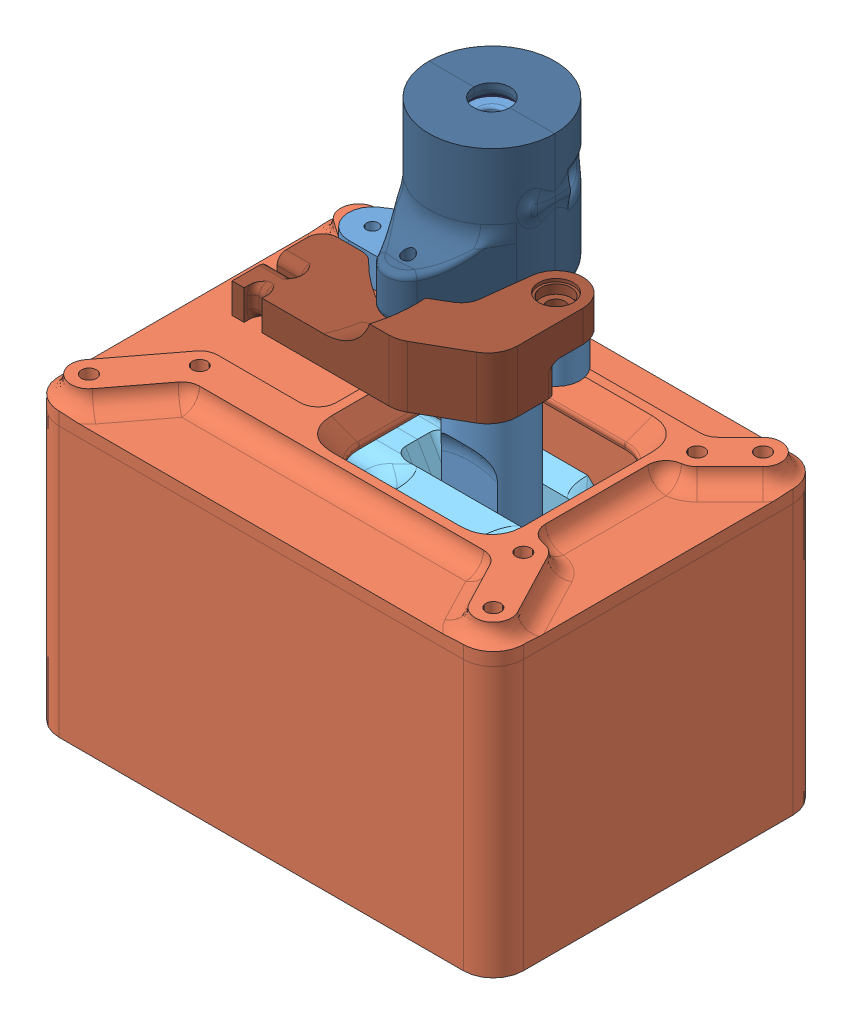
SolidWorks assembly Gimbal, configuration Default. Lengths in mm.
Overall size (155 197.27 110).
24 component instances, 11 part files, 54 mates.
Components (placement in the parent):
- Center Core-1: Center Core [Default] at (14.5 -56 0) size (77.28 158.27 34.47)
- Top Plate-1: Top Plate [Default] at origin size (155 100 110)
- Bearing Block A-1: Bearing Block A [Default] at (54 -21 0) x (0 0 -1) z (1 0 0) size (70 41 12)
- Bearing Block B-1: Bearing Block B [Default] at (-47 -18 0) x (0 0 -1) z (1 0 0) size (81.49 59 37.49)
- Axis B Block-1: Axis B Block [Default] at (14.5 -21 0) x (-1 0 0) z (0 0 -1) size (108 64.09 38.74)
- CAM Roll-1: CAM Roll [Default] at (47.5 -55.5 0) x (0.999997 0.002421 0) z (0 0 1) size (85.5 30 15.96)
- CAM Yaw-1: CAM Yaw [Default] at (-49.75 -49 35) x (0 0 1) z (-1 0 0) size (80 28 17.41)
- Bearing-1: Bearing [685] at (-45.5 -46 0) x (1 0 0) z (0 0.029576 0.999563) size (5 11 11)
- Bearing-2: Bearing [685] at (14.5 -51 4.5) x (0 0 1) z (-0.999911 0.013316 0) size (5 11 11)
- Bearing-3: Bearing [6802] at (14.5 -21 -10.5) x (0 0 1) z (-0.938422 -0.345492 0) size (5 24 24)
- Bearing-4: Bearing [6802] at (50.5 -21 0) size (5 24 24)
- Bearing-5: Bearing [6802] at (-45.5 -21 0) x (1 0 0) z (0 0.145553 0.98935) size (5 24 24)
- Bearing-6: Bearing [6802] at (14.5 -21 10.5) x (0 0 1) z (-0.450494 -0.89278 0) size (5 24 24)
- Bearing-7: Bearing [MF105] at (47.5 -55.5 5.5) x (0 0 1) z (-0.914511 -0.40456 0) size (4 11.6 11.6)
- Bearing-9: Bearing [MF105] at (47.5 -55.5 -5.5) x (0 0 -1) z (0.950341 0.31121 0) size (4 11.6 11.6)
- Bearing-10: Bearing [MF105] at (-52.5 -49 35) x (-1 0 0) z (0 -0.998106 -0.061524) size (4 11.6 11.6)
- Bearing-11: Bearing [MF105] at (-41.5 -49 35) x (1 0 0) z (0 0.59947 0.800397) size (4 11.6 11.6)
- Robenson head bolt-1: Robenson head bolt [Default] at (47.5 -55.5 -19) x (0.990168 0.139885 0) z (0.139885 -0.990168 0) size (9.5 37 9.5)
- Robenson head bolt-2: Robenson head bolt [Default] at (-28 -49 35) x (0 1 0) z (0 0 1) size (9.5 37 9.5)
- Bearing-12: Bearing [6804] at (14.5 63.7723 0) x (0 1 0) z (0.46482 0 0.885405) size (7 32 32)
- Bearing-13: Bearing [6802] at (14.5 99.7723 0) x (0 -1 0) z (0.042392 0 0.999101) size (5 24 24)
- Twist-1: Twist [Default] at (14.5 60.2723 0) size (43.41 47 56.5)
- Bearing-14: Bearing [685] at (14.5 56.7723 28) x (0 -1 0) z (0.058836 0 0.998268) size (5 11 11)
- CAM Twist-1: CAM Twist [Default] at (45.1386 70.7723 9.2345) x (1 0 0) z (0 0 -1) size (76.94 21.7 49.19)
Mates (geometry in assembly coordinates):
- Coincident1: coordinate: point of Top Plate-1
- Coincident2: coincident anti-aligned: plane of Top Plate-1 through (0 0 0) normal (0 -1 0); plane of Bearing Block A-1 through (60 0 35) normal (0 1 0)
- Concentric2: concentric anti-aligned: cylinder of Top Plate-1 through (54 4 29) axis (0 -1 0) radius 2.5; cylinder of Bearing Block A-1 through (54 -10 29) axis (0 1 0) radius 2
- Concentric3: concentric anti-aligned: cylinder of Top Plate-1 through (54 4 -29) axis (0 -1 0) radius 2.5; cylinder of Bearing Block A-1 through (54 -10 -29) axis (0 1 0) radius 2
- Coincident3: coincident anti-aligned: plane of Top Plate-1 through (0 0 0) normal (0 -1 0); plane of Bearing Block B-1 through (-29 0 -35) normal (0 1 0)
- Concentric4: concentric anti-aligned: cylinder of Top Plate-1 through (-54 4 -29) axis (0 -1 0) radius 2.5; cylinder of Bearing Block B-1 through (-54 -10 -29) axis (0 1 0) radius 2
- Concentric5: concentric anti-aligned: cylinder of Top Plate-1 through (-54 4 29) axis (0 -1 0) radius 2.5; cylinder of Bearing Block B-1 through (-54 -10 29) axis (0 1 0) radius 2
- Concentric6: concentric anti-aligned: cylinder of Bearing Block A-1 through (60 -21 0) axis (-1 0 0) radius 9; cylinder of Axis B Block-1 through (14.5 -21 0) axis (1 0 0) radius 7.5
- Coincident4: coincident anti-aligned: plane of Bearing Block A-1 through (48 -36 31.6228) normal (-1 0 0); plane of Axis B Block-1 through (48 -13.5 0) normal (1 0 0)
- Concentric7: concentric anti-aligned: cylinder of Center Core-1 through (14.5 -21 13) axis (0 0 -1) radius 7.5; cylinder of Axis B Block-1 through (14.5 -21 -13) axis (0 0 1) radius 9
- Concentric10: concentric aligned: cylinder of Axis B Block-1 through (-20.5 -46 0) axis (-1 0 0) radius 2.25; cylinder of Bearing-1 through (-55.0787 -46 0) axis (-1 0 0) radius 2.5
- Coincident11: coincident anti-aligned: plane of Axis B Block-1 through (-43 -46 0) normal (-1 0 0); plane of Bearing-1 through (-43 -42.1017 -0.1153) normal (1 0 0)
- Concentric11: concentric anti-aligned: cylinder of Center Core-1 through (14.5 -51 -12) axis (0 0 1) radius 2.25; cylinder of Bearing-2 through (14.5 -51 -5.0787) axis (0 0 -1) radius 2.5
- Coincident12: coincident anti-aligned: plane of Center Core-1 through (14.5 -51 2) normal (0 0 1); plane of Bearing-2 through (14.5519 -47.1003 2) normal (0 0 -1)
- Concentric12: concentric anti-aligned: cylinder of Axis B Block-1 through (14.5 -21 -13) axis (0 0 1) radius 9; cylinder of Bearing-3 through (14.5 -21 -20.0787) axis (0 0 -1) radius 7.5
- Coincident13: coincident anti-aligned: plane of Center Core-1 through (14.5 -21 -8) normal (0 0 -1); plane of Bearing-3 through (11.4251 -12.648 -8) normal (0 0 1)
- Concentric13: concentric aligned: cylinder of Bearing Block A-1 through (60 -21 0) axis (-1 0 0) radius 9; cylinder of Bearing-4 through (40.9213 -21 0) axis (-1 0 0) radius 7.5
- Coincident14: coincident anti-aligned: plane of Axis B Block-1 through (48 -13.5 0) normal (1 0 0); plane of Bearing-4 through (48 -12.1 0) normal (-1 0 0)
- Concentric14: concentric aligned: cylinder of Bearing Block B-1 through (-29 -21 0) axis (-1 0 0) radius 9; cylinder of Bearing-5 through (-55.0787 -21 0) axis (-1 0 0) radius 7.5
- Coincident15: coincident anti-aligned: plane of Axis B Block-1 through (-43 -13.5 0) normal (-1 0 0); plane of Bearing-5 through (-43 -12.1948 -1.2954) normal (1 0 0)
- Concentric15: concentric anti-aligned: cylinder of Axis B Block-1 through (14.5 -21 -13) axis (0 0 1) radius 9; cylinder of Bearing-6 through (14.5 -21 0.9213) axis (0 0 -1) radius 7.5
- Coincident16: coincident anti-aligned: plane of Center Core-1 through (14.5 -21 8) normal (0 0 1); plane of Bearing-6 through (6.5543 -16.9906 8) normal (0 0 -1)
- PathMate1: path: point of Bearing-2; curve of CAM Roll-1; curve of CAM Roll-1
- Concentric23: concentric anti-aligned: cylinder of CAM Roll-1 through (47.5 -55.5 0) axis (0 0 -1) radius 5; cylinder of Bearing-9 through (47.5 -55.5 4.0787) axis (0 0 1) radius 5
- Coincident17: coincident anti-aligned: plane of CAM Roll-1 through (52.5 -55.4879 -6.5) normal (0 0 -1); plane of Bearing-9 through (46.0062 -50.9384 -6.5) normal (0 0 1)
- Concentric24: concentric aligned: cylinder of CAM Roll-1 through (47.5 -55.5 0) axis (0 0 -1) radius 5; cylinder of Bearing-7 through (47.5 -55.5 -4.0787) axis (0 0 -1) radius 5
- Coincident18: coincident anti-aligned: plane of CAM Roll-1 through (52.5 -55.4879 6.5) normal (0 0 1); plane of Bearing-7 through (45.5581 -51.1103 6.5) normal (0 0 -1)
- Concentric25: concentric anti-aligned: cylinder of Axis B Block-1 through (47.5 -55.5 -13) axis (0 0 1) radius 2.5; cylinder of CAM Roll-1 through (47.5 -55.5 13) axis (0 0 -1) radius 3
- Concentric26: concentric aligned: cylinder of CAM Yaw-1 through (-31.23 -49 35) axis (1 0 0) radius 5; cylinder of Bearing-10 through (-42.9213 -49 35) axis (1 0 0) radius 5
- Coincident19: coincident anti-aligned: plane of CAM Yaw-1 through (-53.5 -49 40) normal (-1 0 0); plane of Bearing-10 through (-53.5 -48.7047 30.2091) normal (1 0 0)
- Concentric27: concentric anti-aligned: cylinder of CAM Yaw-1 through (-31.23 -49 35) axis (1 0 0) radius 5; cylinder of Bearing-11 through (-51.0787 -49 35) axis (-1 0 0) radius 5
- Coincident20: coincident anti-aligned: plane of CAM Yaw-1 through (-40.5 -49 40) normal (1 0 0); plane of Bearing-11 through (-40.5 -45.1581 32.1225) normal (-1 0 0)
- Concentric28: concentric anti-aligned: cylinder of Bearing Block B-1 through (-29 -49 35) axis (-1 0 0) radius 2.5; cylinder of CAM Yaw-1 through (-64.75 -49 35) axis (1 0 0) radius 3
- PathMate2: path: point of Bearing-1; curve of CAM Yaw-1; curve of CAM Yaw-1
- LimitAngle1: limit planar angle = 1.268137 rad anti-aligned: plane of Axis B Block-1 through (14.5 -21 0) normal (0 1 0)
- LimitAngle2: limit planar angle = 1.582173 rad: plane of Center Core-1 through (14.5 -56 0) normal (1 0 0); plane of Axis B Block-1 through (14.5 -21 0) normal (0 1 0)
- Concentric29: concentric anti-aligned: cylinder of Axis B Block-1 through (47.5 -55.5 -13) axis (0 0 1) radius 2.5; cylinder of Robenson head bolt-1 through (47.5 -55.5 18) axis (0 0 -1) radius 2.35
- Coincident22: coincident aligned: plane of Axis B Block-1 through (47.5 -55.5 18) normal (0 0 1); plane of Robenson head bolt-1 through (47.5 -55.5 18) normal (0 0 1)
- Coincident23: coincident anti-aligned: plane of Axis B Block-1 through (47.5 -55.5 7.5) normal (0 0 -1); plane of Bearing-7 through (45.9222 -51.9334 7.5) normal (0 0 1)
- Concentric30: concentric anti-aligned: cylinder of Bearing Block B-1 through (-29 -49 35) axis (-1 0 0) radius 2.5; cylinder of Robenson head bolt-2 through (-65 -49 35) axis (1 0 0) radius 2.35
- Coincident24: coincident aligned: plane of Bearing Block B-1 through (-65 -49 35) normal (-1 0 0); plane of Robenson head bolt-2 through (-65 -49 35) normal (-1 0 0)
- Concentric31: concentric anti-aligned: cylinder of Center Core-1 through (14.5 32.826 0) axis (0 1 0) radius 10; cylinder of Bearing-12 through (14.5 54.1937 0) axis (0 -1 0) radius 10
- Coincident25: coincident anti-aligned: plane of Center Core-1 through (14.5 60.2723 10) normal (0 1 0); plane of Bearing-12 through (4.4064 60.2723 5.299) normal (0 -1 0)
- Concentric32: concentric anti-aligned: cylinder of Center Core-1 through (14.5 67.2723 0) axis (0 -1 0) radius 7.5; cylinder of Bearing-13 through (14.5 109.351 0) axis (0 1 0) radius 7.5
- Coincident26: coincident anti-aligned: plane of Center Core-1 through (5.5 97.2723 0) normal (0 1 0); plane of Bearing-13 through (23.392 97.2723 -0.3773) normal (0 -1 0)
- Concentric34: concentric anti-aligned: cylinder of Twist-1 through (14.5 75.2723 28) axis (0 -1 0) radius 2; cylinder of Bearing-14 through (14.5 66.351 28) axis (0 1 0) radius 2.5
- Parallel1: parallel aligned: plane of Center Core-1 through (14.5 102.2723 0) normal (0 1 0)
- Concentric35: concentric aligned: cylinder of Bearing-12 through (14.5 54.1937 0) axis (0 -1 0) radius 16; cylinder of Twist-1 through (14.5 60.2723 0) axis (0 -1 0) radius 16
- Coincident29: coincident anti-aligned: plane of Bearing-12 through (0.3335 67.2723 7.4371) normal (0 1 0); plane of Twist-1 through (14.5 67.2723 16) normal (0 -1 0)
- Distance1: distance = 1 mm anti-aligned: plane of Twist-1 through (14.5 60.2723 16) normal (0 -1 0); plane of Bearing-14 through (18.3932 59.2723 27.7705) normal (0 1 0)
- Parallel3: parallel aligned: plane of Twist-1 through (14.5 60.2723 0) normal (1 0 0)
- Concentric36: concentric: cylinder of Center Core-1 through (45.1386 37.2723 9.2345) axis (0 1 0) radius 2; cylinder of CAM Twist-1 through (45.1386 64.2723 9.2345) axis (0 -1 0) radius 5
- Distance2: distance = 1 mm: plane of CAM Twist-1 through (45.1386 60.2723 9.2345) normal (0 -1 0); plane of Center Core-1 through (14.5 59.2723 11.5) normal (0 1 0)
- Parallel4: parallel anti-aligned: plane of Center Core-1 through (-16.1386 37.2723 17.2345) normal (0 0 1); plane of CAM Twist-1 through (45.1386 60.2723 19.2345) normal (0 0 -1)
